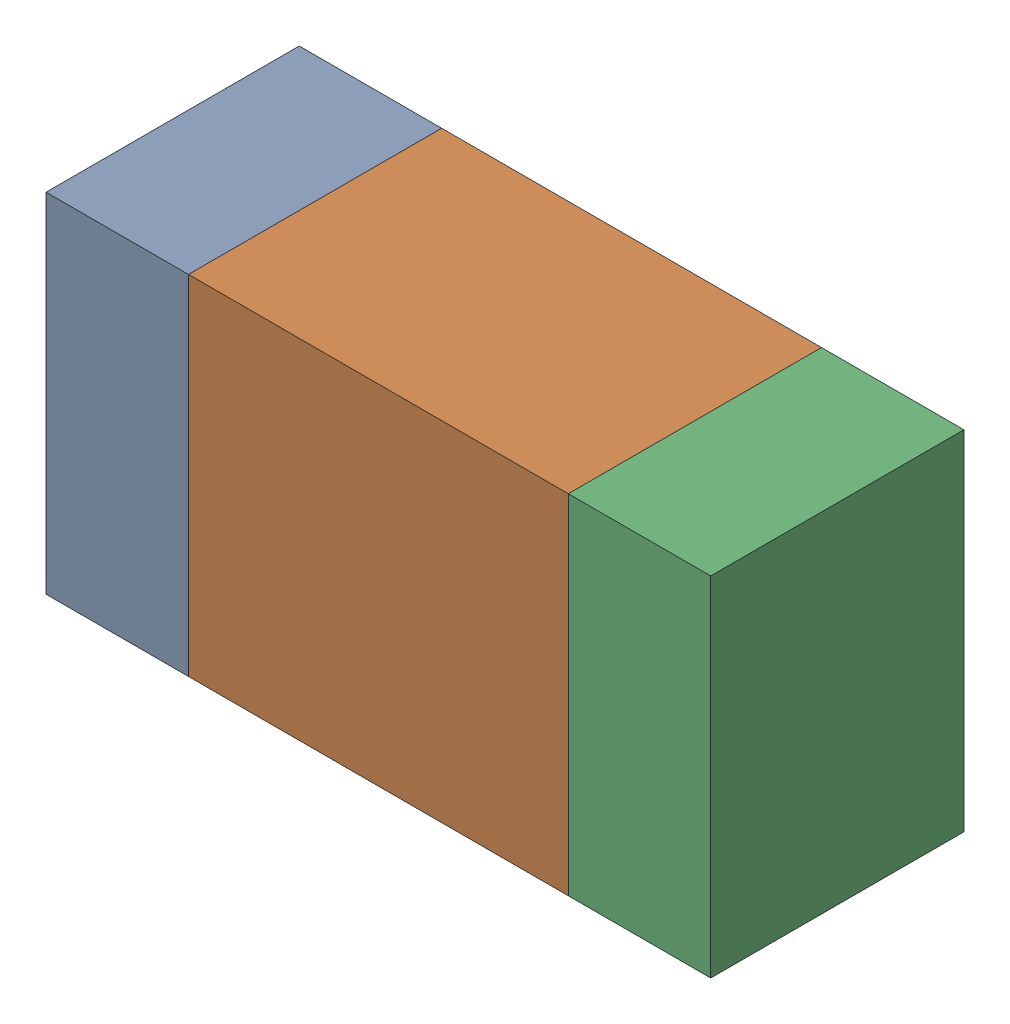
SolidWorks assembly R209PCB, configuration Default. Lengths in mm.
Overall size (1.05 0.55 0.4).
6 component instances, 2 part files, 0 mates.
Components (placement in the parent):
- 854785432-1: 854785432 [Default] at (85.3874 126.1999 0) size (0.22 0.55 0.4)
  - Extruded-1: Extruded [Default] at origin size (0.22 0.55 0.4)
- 854785568-1: 854785568 [Default] at (85.7999 126.1999 0) size (0.6 0.55 0.4)
  - Extruded_2-1: Extruded_2 [Default] at origin size (0.6 0.55 0.4)
- 854785432-2: 854785432 [Default] at (86.2124 126.1999 0) size (0.22 0.55 0.4)
  - Extruded-1: Extruded [Default] at origin size (0.22 0.55 0.4)
